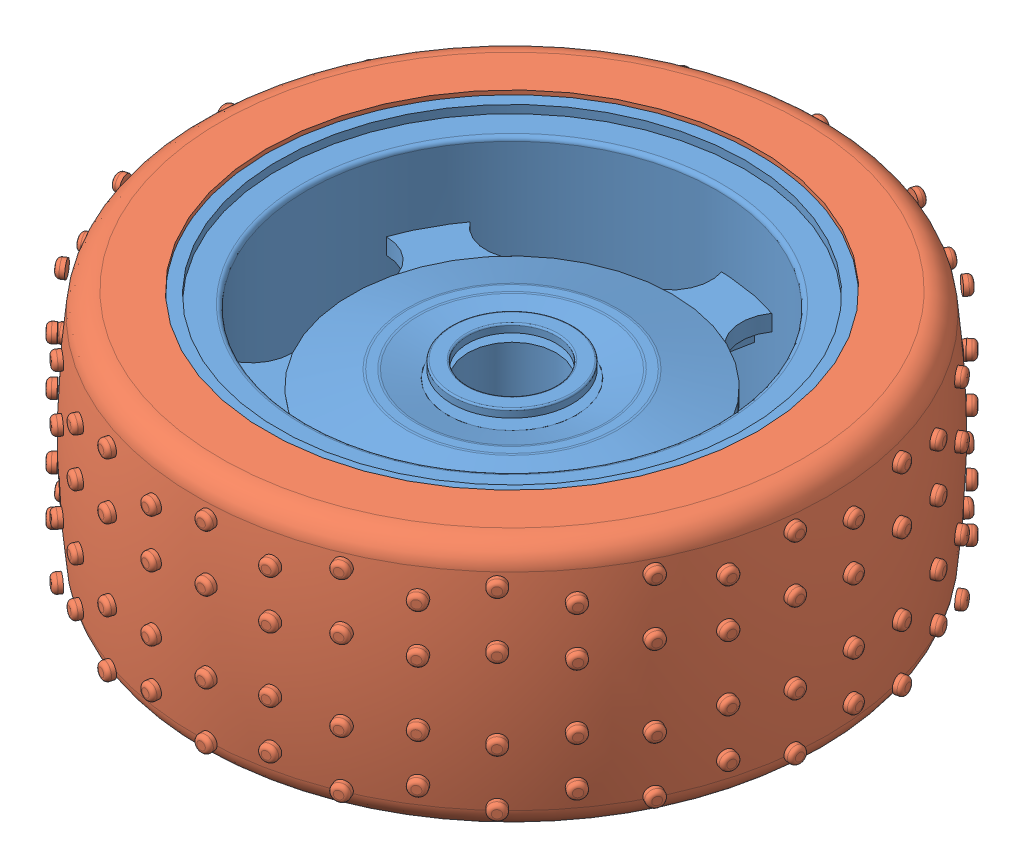
SolidWorks assembly tire, configuration Default. Lengths in mm.
Overall size (115.91 31.01 115.91).
2 component instances, 2 part files, 0 mates.
Components (placement in the parent):
- tire_rim-1: tire_rim [Default] at (-0.9296 -18.1541 0) size (61 30 61)
- tire_rubber-1: tire_rubber [Default] at (-0.9296 -3.1541 0) x (0 -1 0) z (0.683949 0 0.729529) size (31.01 82 82)
